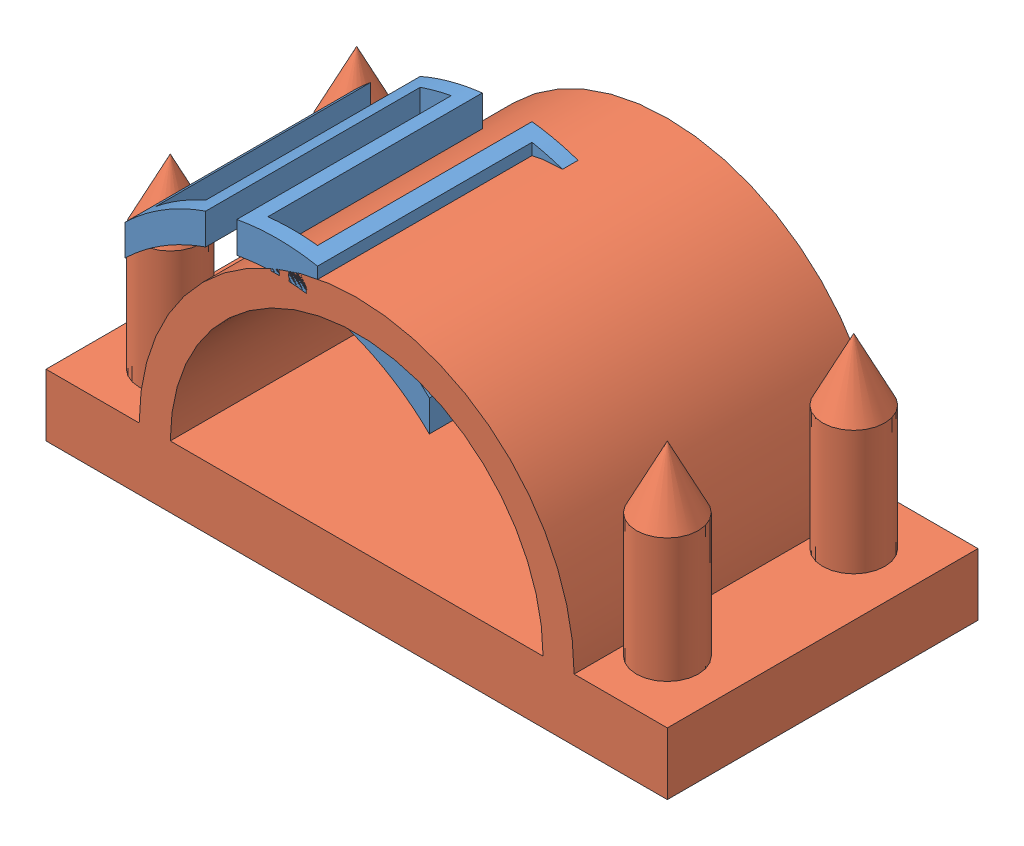
SolidWorks assembly Assem1, configuration Default. Lengths in mm.
Overall size (100 46.92 50.22).
2 component instances, 2 part files, 1 mates.
Components (placement in the parent):
- 3d-print-top-2: 3d-print-top [Default] at (-30.071 -14.5654 35.8341) size (49.02 15.12 37.47)
- conformal_substrate_top-4: conformal_substrate_top [Default] at (-17.2722 -21.3907 29.3853) size (100 45 50)
Mates (geometry in assembly coordinates):
- Coincident3: coincident anti-aligned: plane of 3d-print-top-2 through (-36.571 19.8257 54.3853) normal (0 0 1); circle of conformal_substrate_top-4
